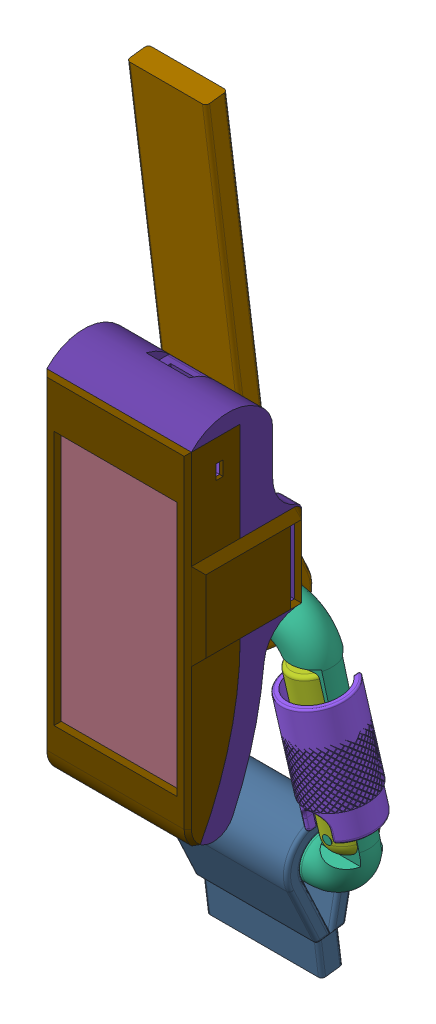
SolidWorks assembly P4_ASSEMBLY, configuration Default. Lengths in mm.
Overall size (66.23 222.78 54.07).
74 component instances, 29 part files, 212 mates.
Components (placement in the parent):
- P4_BTG 3.7V 150mAh LIPO-1: P4_BTG 3.7V 150mAh LIPO [Default] at (27.905 51.2971 -9.81) x (0 -1 0) z (-1 0 0) size (26 7 18.75)
- P4_CAPC-0805-T1.35-BN-1: P4_CAPC-0805-T1.35-BN [Default] at (18.3512 20.3637 -0.675) x (0 1 0) z (-1 0 0) size (2.1 1.35 1.35)
- P4_RESC-0805-1: P4_RESC-0805 [Default] at (24.182 63.4727 0) x (-1 0 0) z (0 0 -1) size (2.1 1.35 0.6)
- P4_RESC-0805-2: P4_RESC-0805 [Default] at (24.1365 57.0909 0) x (-1 0 0) z (0 0 -1) size (2.1 1.35 0.6)
- P4_RESC-0805-4: P4_RESC-0805 [Default] at (24.0502 60.9416 0) x (1 0 0) z (0 0 -1) size (2.1 1.35 0.6)
- P4_soic-14-1: P4_soic-14 [Default] at (16.3896 59.7284 -0.9779) x (0 -1 0) z (1 0 0) size (8.65 1.6 6.05)
- P4_MICRO_SD_WITH_SLOT-1: P4_MICRO_SD_WITH_SLOT [Default] at (56.0581 -187.6439 -121.4036) x (0 0 -1) z (0 1 0) size (2.44 17.9 16)
- P4_MS5611NOBREAKOUT-1: P4_MS5611NOBREAKOUT [Default] at (31.3803 12.3031 -1.5) x (0 1 0) z (-1 0 0) size (5.08 1.5 3.07)
- P4_TACTILE_SWITCH_SIDE-2: P4_TACTILE_SWITCH_SIDE [Default] at (3.8 59.5977 -4.2856) x (0 1 0) z (0 0 1) size (6.8 8.34 8.73)
- P4_BOT-03D PASSIVE BUZZER-1: P4_BOT-03D PASSIVE BUZZER [Default] at (31.8 58.2086 -0.3) x (0 1 0) z (-1 0 0) size (12.6 3.6 11)
- P4_AB2_USB_MICRO_SMD-2: P4_AB2_USB_MICRO_SMD [Default] at (19.0065 148.0155 -12.6975) x (-1 0 0) z (0 1 0) size (7.99 3.56 5.59)
- P4_JST 2pin rightangle-2: P4_JST 2pin rightangle [Default] at (30.445 58.185 -12.31) x (0 1 0) z (1 0 0) size (8 6.3 7.62)
- P4_BLUEFRUIT FEATHER-2: P4_BLUEFRUIT FEATHER [Default] at (30.445 66 -13.81) x (0 -1 0) z (-1 0 0) size (50.98 4.5 22.86)
- P4_1PIN_8.25_SHORT_SOCKET-44: P4_1PIN_8.25_SHORT_SOCKET [Default] at (8.855 24 -12.31) x (0 1 0) z (0 0 1) size (2.54 2.54 11.81)
- P4_1PIN_8.25_SHORT_SOCKET-45: P4_1PIN_8.25_SHORT_SOCKET [Default] at (8.855 26.54 -12.31) x (0 1 0) z (0 0 1) size (2.54 2.54 11.81)
- P4_1PIN_8.25_SHORT_SOCKET-46: P4_1PIN_8.25_SHORT_SOCKET [Default] at (8.855 29.08 -12.31) x (0 1 0) z (0 0 1) size (2.54 2.54 11.81)
- P4_1PIN_8.25_SHORT_SOCKET-47: P4_1PIN_8.25_SHORT_SOCKET [Default] at (8.855 31.62 -12.31) x (0 1 0) z (0 0 1) size (2.54 2.54 11.81)
- P4_1PIN_8.25_SHORT_SOCKET-48: P4_1PIN_8.25_SHORT_SOCKET [Default] at (8.855 34.16 -12.31) x (0 1 0) z (0 0 1) size (2.54 2.54 11.81)
- P4_1PIN_8.25_SHORT_SOCKET-49: P4_1PIN_8.25_SHORT_SOCKET [Default] at (8.855 36.7 -12.31) x (0 1 0) z (0 0 1) size (2.54 2.54 11.81)
- P4_1PIN_8.25_SHORT_SOCKET-50: P4_1PIN_8.25_SHORT_SOCKET [Default] at (8.855 39.24 -12.31) x (0 1 0) z (0 0 1) size (2.54 2.54 11.81)
- P4_1PIN_8.25_SHORT_SOCKET-51: P4_1PIN_8.25_SHORT_SOCKET [Default] at (8.855 41.78 -12.31) x (0 1 0) z (0 0 1) size (2.54 2.54 11.81)
- P4_1PIN_8.25_SHORT_SOCKET-52: P4_1PIN_8.25_SHORT_SOCKET [Default] at (8.855 44.32 -12.31) x (0 1 0) z (0 0 1) size (2.54 2.54 11.81)
- P4_1PIN_8.25_SHORT_SOCKET-53: P4_1PIN_8.25_SHORT_SOCKET [Default] at (8.855 46.86 -12.31) x (0 1 0) z (0 0 1) size (2.54 2.54 11.81)
- P4_1PIN_8.25_SHORT_SOCKET-54: P4_1PIN_8.25_SHORT_SOCKET [Default] at (8.855 49.4 -12.31) x (0 1 0) z (0 0 1) size (2.54 2.54 11.81)
- P4_1PIN_8.25_SHORT_SOCKET-55: P4_1PIN_8.25_SHORT_SOCKET [Default] at (8.855 51.94 -12.31) x (0 1 0) z (0 0 1) size (2.54 2.54 11.81)
- P4_1PIN_8.25_SHORT_SOCKET-56: P4_1PIN_8.25_SHORT_SOCKET [Default] at (8.855 54.48 -12.31) x (0 1 0) z (0 0 1) size (2.54 2.54 11.81)
- P4_1PIN_8.25_SHORT_SOCKET-57: P4_1PIN_8.25_SHORT_SOCKET [Default] at (8.855 57.02 -12.31) x (0 1 0) z (0 0 1) size (2.54 2.54 11.81)
- P4_1PIN_8.25_SHORT_SOCKET-58: P4_1PIN_8.25_SHORT_SOCKET [Default] at (8.855 59.56 -12.31) x (0 1 0) z (0 0 1) size (2.54 2.54 11.81)
- P4_1PIN_8.25_SHORT_SOCKET-59: P4_1PIN_8.25_SHORT_SOCKET [Default] at (8.855 21.46 -12.31) x (0 1 0) z (0 0 1) size (2.54 2.54 11.81)
- P4_1PIN_8.25_SHORT_SOCKET-60: P4_1PIN_8.25_SHORT_SOCKET [Default] at (29.175 49.4 -12.31) x (0 1 0) z (0 0 1) size (2.54 2.54 11.81)
- P4_1PIN_8.25_SHORT_SOCKET-61: P4_1PIN_8.25_SHORT_SOCKET [Default] at (29.175 46.86 -12.31) x (0 1 0) z (0 0 1) size (2.54 2.54 11.81)
- P4_1PIN_8.25_SHORT_SOCKET-62: P4_1PIN_8.25_SHORT_SOCKET [Default] at (29.175 44.32 -12.31) x (0 1 0) z (0 0 1) size (2.54 2.54 11.81)
- P4_1PIN_8.25_SHORT_SOCKET-63: P4_1PIN_8.25_SHORT_SOCKET [Default] at (29.175 41.78 -12.31) x (0 1 0) z (0 0 1) size (2.54 2.54 11.81)
- P4_1PIN_8.25_SHORT_SOCKET-64: P4_1PIN_8.25_SHORT_SOCKET [Default] at (29.175 39.24 -12.31) x (0 1 0) z (0 0 1) size (2.54 2.54 11.81)
- P4_1PIN_8.25_SHORT_SOCKET-65: P4_1PIN_8.25_SHORT_SOCKET [Default] at (29.175 36.7 -12.31) x (0 1 0) z (0 0 1) size (2.54 2.54 11.81)
- P4_1PIN_8.25_SHORT_SOCKET-66: P4_1PIN_8.25_SHORT_SOCKET [Default] at (29.175 34.16 -12.31) x (0 1 0) z (0 0 1) size (2.54 2.54 11.81)
- P4_1PIN_8.25_SHORT_SOCKET-67: P4_1PIN_8.25_SHORT_SOCKET [Default] at (29.175 31.62 -12.31) x (0 1 0) z (0 0 1) size (2.54 2.54 11.81)
- P4_1PIN_8.25_SHORT_SOCKET-68: P4_1PIN_8.25_SHORT_SOCKET [Default] at (29.175 29.08 -12.31) x (0 1 0) z (0 0 1) size (2.54 2.54 11.81)
- P4_1PIN_8.25_SHORT_SOCKET-69: P4_1PIN_8.25_SHORT_SOCKET [Default] at (29.175 26.54 -12.31) x (0 1 0) z (0 0 1) size (2.54 2.54 11.81)
- P4_1PIN_8.25_SHORT_SOCKET-70: P4_1PIN_8.25_SHORT_SOCKET [Default] at (29.175 24 -12.31) x (0 1 0) z (0 0 1) size (2.54 2.54 11.81)
- P4_1PIN_8.25_SHORT_SOCKET-71: P4_1PIN_8.25_SHORT_SOCKET [Default] at (29.175 21.46 -12.31) x (0 1 0) z (0 0 1) size (2.54 2.54 11.81)
- Part2^P4_ASSEMBLY-1: Part2^P4_ASSEMBLY [Default] at origin (virtual)
- P4_2.9_EPD-1: P4_2.9_EPD [Default] at (38 66.02 3.13) x (-1 0 0) z (0 1 0) size (38 8.3 89.5)
  - P4_2.9_EPD-1: P4_2.9_EPD [Default] at origin size (38 3.55 89.5)
  - P4_JST XH 8 S8B-XH-A1 shrouded header connector v4-1: P4_JST XH 8 S8B-XH-A1 shrouded header connector v4 [Default] at (19 -2.875 -82.5) x (-1 0 0) z (0 0 -1) size (22.68 5.75 10.45)
  - P4_FPC_24-1: P4_FPC_24 [Valor predeterminado] at (23 -2.13 -7.2471) x (1 0 0) z (0 1 0) size (16.4 6.45 2.13)
- P4_PCB_FOR_2.9_EPD-1: P4_PCB_FOR_2.9_EPD [Default] at (0 66 1) x (1 0 0) z (0 1 0) size (38 1 66)
- P4_2.9_EPD_CASE_BACK-1: P4_2.9_EPD_CASE_BACK [Default] at (38.015 -27.6516 -35.2894) x (0 1 0) z (-1 0 0) size (100.85 30.49 40)
- P4_2.9_EPD_CASE_COVER-1: P4_2.9_EPD_CASE_COVER [Default] at (0 -6.6251 5.68) x (0 1 0) z (0 0 1) size (95.4 44 31.49)
- P4_SO8-1: P4_SO8 [Default] at (15.2666 50.6882 0) x (1 0 0) z (0 1 0) size (5 1.75 6.2)
- P4_SOT23-1: P4_SOT23 [Predeterminado] at (22.8563 53.2581 -0.6726) x (-1 0 0) z (0 0 -1) size (3 2.25 1.22)
- P4_RESC-0805-8: P4_RESC-0805 [Default] at (22.7629 48.0366 0) x (0 1 0) z (0 0 -1) size (2.1 1.35 0.6)
- P4_878980426-1: P4_878980426 [Default] at (8.84 35.43 -2.565) x (0 1 0) z (-1 0 0) size (10.16 9.65 4.8)
- P4_878980426-2: P4_878980426 [Default] at (8.84 25.27 -2.565) x (0 1 0) z (-1 0 0) size (10.16 9.65 4.8)
- P4_878980426-3: P4_878980426 [Default] at (29.16 35.43 -2.565) x (0 1 0) z (-1 0 0) size (10.16 9.65 4.8)
- P4_878980426-4: P4_878980426 [Default] at (8.84 55.75 -2.565) x (0 1 0) z (-1 0 0) size (10.16 9.65 4.8)
- P4_878980426-5: P4_878980426 [Default] at (29.16 45.59 -2.565) x (0 1 0) z (-1 0 0) size (10.16 9.65 4.8)
- P4_878980426-6: P4_878980426 [Default] at (29.16 25.27 -2.565) x (0 1 0) z (-1 0 0) size (10.16 9.65 4.8)
- P4_878980426-7: P4_878980426 [Default] at (8.84 45.59 -2.565) x (0 1 0) z (-1 0 0) size (10.16 9.65 4.8)
- P4_SPACER-1: P4_SPACER [Default] at (38 -23.48 3.13) x (-1 0 0) z (0 -1 0) size (38 3.13 70.25)
- P4_SMT_RA_PIN-1: P4_SMT_RA_PIN [Default] at (24.03 10.67 0) x (0 -1 0) z (1 0 0) size (12.95 3.56 2.54)
- P4_SMT_RA_PIN-2: P4_SMT_RA_PIN [Default] at (26.57 10.67 0) x (0 -1 0) z (1 0 0) size (12.95 3.56 2.54)
- P4_SMT_RA_PIN-3: P4_SMT_RA_PIN [Default] at (18.95 10.67 0) x (0 -1 0) z (1 0 0) size (12.95 3.56 2.54)
- P4_SMT_RA_PIN-4: P4_SMT_RA_PIN [Default] at (21.49 10.67 0) x (0 -1 0) z (1 0 0) size (12.95 3.56 2.54)
- P4_SMT_RA_PIN-5: P4_SMT_RA_PIN [Default] at (31.65 10.67 0) x (0 -1 0) z (1 0 0) size (12.95 3.56 2.54)
- P4_SMT_RA_PIN-6: P4_SMT_RA_PIN [Default] at (29.11 10.67 0) x (0 -1 0) z (1 0 0) size (12.95 3.56 2.54)
- P4_SMT_RA_PIN-7: P4_SMT_RA_PIN [Default] at (36.73 10.67 0) x (0 -1 0) z (1 0 0) size (12.95 3.56 2.54)
- P4_SMT_RA_PIN-8: P4_SMT_RA_PIN [Default] at (34.19 10.67 0) x (0 -1 0) z (1 0 0) size (12.95 3.56 2.54)
- CARABINER SUP AIR Ø12-1: CARABINER SUP AIR Ø12 [Default] at (19.0561 -21.0823 -30.0124) x (1 0 0) z (0 -0.122208 0.992504) size (66.23 74 18.01)
  - ALÇA-1: ALÇA [Default] at origin size (63.85 74 12.79)
  - GATILHO-1: GATILHO [Default] at (26.2233 -22.952 0) x (0.990404 0.138202 0) z (0 0 1) size (12 45.37 12.12)
  - FECHO-1: FECHO [Default] at (25.3718 -16.8504 0) x (0.990404 0.138202 0) z (0 0 1) size (18.01 33.07 18.01)
- RISER-1: RISER [Default] at (7.015 9.6853 -26.2239) x (1 0 0) z (0 -0.122208 0.992504) size (24 140 20)
- HARNESS-1: HARNESS [Default] at (1.9827 -51.85 -33.8009) x (1 0 0) z (0 0.122208 -0.992504) size (34 40 20)
Mates (geometry in assembly coordinates):
- Coincident628: coincident anti-aligned: plane of P4_BTG 3.7V 150mAh LIPO-1 through (27.905 51.2971 -9.81) normal (0 0 -1); plane of P4_BLUEFRUIT FEATHER-2 through (30.445 66 -9.81) normal (0 0 1)
- Coincident376: coincident aligned: plane of P4_PCB_FOR_2.9_EPD-1 through (0 66 0) normal (-1 0 0); plane of P4_TACTILE_SWITCH_SIDE-2 through (0 59.5977 -4.2856) normal (-1 0 0)
- Coincident433: coincident anti-aligned: plane of P4_AB2_USB_MICRO_SMD-2 through (19.0065 66 -12.31) normal (0 0 -1); plane of P4_BLUEFRUIT FEATHER-2 through (27.815 17.65 -12.31) normal (0 0 1)
- Parallel22: parallel aligned: line of P4_AB2_USB_MICRO_SMD-2 through (21.4522 66 -12.3752) axis (-1 0 0); line of P4_BLUEFRUIT FEATHER-2 through (27.815 66 -12.31) axis (-1 0 0)
- Coincident434: coincident aligned: plane of P4_JST 2pin rightangle-2 through (30.445 52.4192 -12.31) normal (1 0 0); plane of P4_BLUEFRUIT FEATHER-2 through (30.445 63.37 -12.31) normal (1 0 0)
- Coincident435: coincident: line of P4_AB2_USB_MICRO_SMD-2 through (21.9513 66 -9.7692) axis (-1 0 0); plane of P4_BLUEFRUIT FEATHER-2 through (27.815 66 -12.31) normal (0 1 0)
- Coincident436: coincident anti-aligned: plane of P4_JST 2pin rightangle-2 through (26.635 55.3021 -12.31) normal (0 0 -1); plane of P4_BLUEFRUIT FEATHER-2 through (27.815 17.65 -12.31) normal (0 0 1)
- Distance27: distance = 6.7 mm aligned: plane of P4_JST 2pin rightangle-2 through (30.445 59.3 -12.31) normal (0 1 0); plane of P4_BLUEFRUIT FEATHER-2 through (27.815 66 -12.31) normal (0 1 0)
- Parallel23: parallel aligned: plane of P4_BOT-03D PASSIVE BUZZER-1 through (38 55.7086 -3.6) normal (1 0 0); plane of P4_BLUEFRUIT FEATHER-2 through (30.445 63.37 -12.31) normal (1 0 0)
- LimitDistance11: limit distance = 0.0071 mm anti-aligned: plane of P4_BTG 3.7V 150mAh LIPO-1 through (27.905 51.2971 -2.81) normal (0 1 0); plane of P4_JST 2pin rightangle-2 through (30.445 51.3042 -12.31) normal (0 -1 0)
- Coincident458: coincident aligned: plane of P4_1PIN_8.25_SHORT_SOCKET-57 through (7.585 57.02 -3.81) normal (-1 0 0); plane of P4_1PIN_8.25_SHORT_SOCKET-58 through (7.585 59.56 -3.81) normal (-1 0 0)
- Coincident459: coincident aligned: plane of P4_1PIN_8.25_SHORT_SOCKET-56 through (7.585 54.48 -3.81) normal (-1 0 0); plane of P4_1PIN_8.25_SHORT_SOCKET-57 through (7.585 57.02 -3.81) normal (-1 0 0)
- Coincident460: coincident aligned: plane of P4_1PIN_8.25_SHORT_SOCKET-55 through (7.585 51.94 -3.81) normal (-1 0 0); plane of P4_1PIN_8.25_SHORT_SOCKET-56 through (7.585 54.48 -3.81) normal (-1 0 0)
- Coincident461: coincident aligned: plane of P4_1PIN_8.25_SHORT_SOCKET-54 through (7.585 49.4 -3.81) normal (-1 0 0); plane of P4_1PIN_8.25_SHORT_SOCKET-55 through (7.585 51.94 -3.81) normal (-1 0 0)
- Coincident462: coincident aligned: plane of P4_1PIN_8.25_SHORT_SOCKET-53 through (7.585 46.86 -3.81) normal (-1 0 0); plane of P4_1PIN_8.25_SHORT_SOCKET-54 through (7.585 49.4 -3.81) normal (-1 0 0)
- Coincident463: coincident aligned: plane of P4_1PIN_8.25_SHORT_SOCKET-52 through (7.585 44.32 -3.81) normal (-1 0 0); plane of P4_1PIN_8.25_SHORT_SOCKET-53 through (7.585 46.86 -3.81) normal (-1 0 0)
- Coincident464: coincident aligned: plane of P4_1PIN_8.25_SHORT_SOCKET-51 through (7.585 41.78 -3.81) normal (-1 0 0); plane of P4_1PIN_8.25_SHORT_SOCKET-52 through (7.585 44.32 -3.81) normal (-1 0 0)
- Coincident465: coincident aligned: plane of P4_1PIN_8.25_SHORT_SOCKET-50 through (7.585 39.24 -3.81) normal (-1 0 0); plane of P4_1PIN_8.25_SHORT_SOCKET-51 through (7.585 41.78 -3.81) normal (-1 0 0)
- Coincident466: coincident aligned: plane of P4_1PIN_8.25_SHORT_SOCKET-49 through (7.585 36.7 -3.81) normal (-1 0 0); plane of P4_1PIN_8.25_SHORT_SOCKET-50 through (7.585 39.24 -3.81) normal (-1 0 0)
- Coincident467: coincident aligned: plane of P4_1PIN_8.25_SHORT_SOCKET-48 through (7.585 34.16 -3.81) normal (-1 0 0); plane of P4_1PIN_8.25_SHORT_SOCKET-49 through (7.585 36.7 -3.81) normal (-1 0 0)
- Coincident468: coincident aligned: plane of P4_1PIN_8.25_SHORT_SOCKET-47 through (7.585 31.62 -3.81) normal (-1 0 0); plane of P4_1PIN_8.25_SHORT_SOCKET-48 through (7.585 34.16 -3.81) normal (-1 0 0)
- Coincident469: coincident aligned: plane of P4_1PIN_8.25_SHORT_SOCKET-46 through (7.585 29.08 -3.81) normal (-1 0 0); plane of P4_1PIN_8.25_SHORT_SOCKET-47 through (7.585 31.62 -3.81) normal (-1 0 0)
- Coincident470: coincident aligned: plane of P4_1PIN_8.25_SHORT_SOCKET-45 through (7.585 26.54 -3.81) normal (-1 0 0); plane of P4_1PIN_8.25_SHORT_SOCKET-46 through (7.585 29.08 -3.81) normal (-1 0 0)
- Coincident471: coincident aligned: plane of P4_1PIN_8.25_SHORT_SOCKET-44 through (7.585 24 -3.81) normal (-1 0 0); plane of P4_1PIN_8.25_SHORT_SOCKET-45 through (7.585 26.54 -3.81) normal (-1 0 0)
- Coincident472: coincident anti-aligned: plane of P4_1PIN_8.25_SHORT_SOCKET-57 through (8.855 58.29 -3.81) normal (0 1 0); plane of P4_1PIN_8.25_SHORT_SOCKET-58 through (8.855 58.29 -3.81) normal (0 -1 0)
- Coincident473: coincident anti-aligned: plane of P4_1PIN_8.25_SHORT_SOCKET-56 through (8.855 55.75 -3.81) normal (0 1 0); plane of P4_1PIN_8.25_SHORT_SOCKET-57 through (8.855 55.75 -3.81) normal (0 -1 0)
- Coincident474: coincident anti-aligned: plane of P4_1PIN_8.25_SHORT_SOCKET-55 through (8.855 53.21 -3.81) normal (0 1 0); plane of P4_1PIN_8.25_SHORT_SOCKET-56 through (8.855 53.21 -3.81) normal (0 -1 0)
- Coincident475: coincident anti-aligned: plane of P4_1PIN_8.25_SHORT_SOCKET-54 through (8.855 50.67 -3.81) normal (0 1 0); plane of P4_1PIN_8.25_SHORT_SOCKET-55 through (8.855 50.67 -3.81) normal (0 -1 0)
- Coincident476: coincident anti-aligned: plane of P4_1PIN_8.25_SHORT_SOCKET-53 through (8.855 48.13 -3.81) normal (0 1 0); plane of P4_1PIN_8.25_SHORT_SOCKET-54 through (8.855 48.13 -3.81) normal (0 -1 0)
- Coincident477: coincident anti-aligned: plane of P4_1PIN_8.25_SHORT_SOCKET-52 through (8.855 45.59 -3.81) normal (0 1 0); plane of P4_1PIN_8.25_SHORT_SOCKET-53 through (8.855 45.59 -3.81) normal (0 -1 0)
- Coincident478: coincident anti-aligned: plane of P4_1PIN_8.25_SHORT_SOCKET-51 through (8.855 43.05 -3.81) normal (0 1 0); plane of P4_1PIN_8.25_SHORT_SOCKET-52 through (8.855 43.05 -3.81) normal (0 -1 0)
- Coincident479: coincident anti-aligned: plane of P4_1PIN_8.25_SHORT_SOCKET-50 through (8.855 40.51 -3.81) normal (0 1 0); plane of P4_1PIN_8.25_SHORT_SOCKET-51 through (8.855 40.51 -3.81) normal (0 -1 0)
- Coincident480: coincident anti-aligned: plane of P4_1PIN_8.25_SHORT_SOCKET-49 through (8.855 37.97 -3.81) normal (0 1 0); plane of P4_1PIN_8.25_SHORT_SOCKET-50 through (8.855 37.97 -3.81) normal (0 -1 0)
- Coincident481: coincident anti-aligned: plane of P4_1PIN_8.25_SHORT_SOCKET-48 through (8.855 35.43 -3.81) normal (0 1 0); plane of P4_1PIN_8.25_SHORT_SOCKET-49 through (8.855 35.43 -3.81) normal (0 -1 0)
- Coincident482: coincident anti-aligned: plane of P4_1PIN_8.25_SHORT_SOCKET-47 through (8.855 32.89 -3.81) normal (0 1 0); plane of P4_1PIN_8.25_SHORT_SOCKET-48 through (8.855 32.89 -3.81) normal (0 -1 0)
- Coincident483: coincident anti-aligned: plane of P4_1PIN_8.25_SHORT_SOCKET-46 through (8.855 30.35 -3.81) normal (0 1 0); plane of P4_1PIN_8.25_SHORT_SOCKET-47 through (8.855 30.35 -3.81) normal (0 -1 0)
- Coincident484: coincident anti-aligned: plane of P4_1PIN_8.25_SHORT_SOCKET-45 through (8.855 27.81 -3.81) normal (0 1 0); plane of P4_1PIN_8.25_SHORT_SOCKET-46 through (8.855 27.81 -3.81) normal (0 -1 0)
- Coincident485: coincident anti-aligned: plane of P4_1PIN_8.25_SHORT_SOCKET-44 through (8.855 25.27 -3.81) normal (0 1 0); plane of P4_1PIN_8.25_SHORT_SOCKET-45 through (8.855 25.27 -3.81) normal (0 -1 0)
- Coincident486: coincident aligned: plane of P4_1PIN_8.25_SHORT_SOCKET-57 through (8.855 57.02 -3.81) normal (0 0 1); plane of P4_1PIN_8.25_SHORT_SOCKET-58 through (8.855 59.56 -3.81) normal (0 0 1)
- Coincident487: coincident aligned: plane of P4_1PIN_8.25_SHORT_SOCKET-56 through (8.855 54.48 -3.81) normal (0 0 1); plane of P4_1PIN_8.25_SHORT_SOCKET-57 through (8.855 57.02 -3.81) normal (0 0 1)
- Coincident488: coincident aligned: plane of P4_1PIN_8.25_SHORT_SOCKET-55 through (8.855 51.94 -3.81) normal (0 0 1); plane of P4_1PIN_8.25_SHORT_SOCKET-56 through (8.855 54.48 -3.81) normal (0 0 1)
- Coincident489: coincident aligned: plane of P4_1PIN_8.25_SHORT_SOCKET-54 through (8.855 49.4 -3.81) normal (0 0 1); plane of P4_1PIN_8.25_SHORT_SOCKET-55 through (8.855 51.94 -3.81) normal (0 0 1)
- Coincident490: coincident aligned: plane of P4_1PIN_8.25_SHORT_SOCKET-53 through (8.855 46.86 -3.81) normal (0 0 1); plane of P4_1PIN_8.25_SHORT_SOCKET-54 through (8.855 49.4 -3.81) normal (0 0 1)
- Coincident491: coincident aligned: plane of P4_1PIN_8.25_SHORT_SOCKET-52 through (8.855 44.32 -3.81) normal (0 0 1); plane of P4_1PIN_8.25_SHORT_SOCKET-53 through (8.855 46.86 -3.81) normal (0 0 1)
- Coincident492: coincident aligned: plane of P4_1PIN_8.25_SHORT_SOCKET-51 through (8.855 41.78 -3.81) normal (0 0 1); plane of P4_1PIN_8.25_SHORT_SOCKET-52 through (8.855 44.32 -3.81) normal (0 0 1)
- Coincident493: coincident aligned: plane of P4_1PIN_8.25_SHORT_SOCKET-50 through (8.855 39.24 -3.81) normal (0 0 1); plane of P4_1PIN_8.25_SHORT_SOCKET-51 through (8.855 41.78 -3.81) normal (0 0 1)
- Coincident494: coincident aligned: plane of P4_1PIN_8.25_SHORT_SOCKET-49 through (8.855 36.7 -3.81) normal (0 0 1); plane of P4_1PIN_8.25_SHORT_SOCKET-50 through (8.855 39.24 -3.81) normal (0 0 1)
- Coincident495: coincident aligned: plane of P4_1PIN_8.25_SHORT_SOCKET-48 through (8.855 34.16 -3.81) normal (0 0 1); plane of P4_1PIN_8.25_SHORT_SOCKET-49 through (8.855 36.7 -3.81) normal (0 0 1)
- Coincident496: coincident aligned: plane of P4_1PIN_8.25_SHORT_SOCKET-47 through (8.855 31.62 -3.81) normal (0 0 1); plane of P4_1PIN_8.25_SHORT_SOCKET-48 through (8.855 34.16 -3.81) normal (0 0 1)
- Coincident497: coincident aligned: plane of P4_1PIN_8.25_SHORT_SOCKET-46 through (8.855 29.08 -3.81) normal (0 0 1); plane of P4_1PIN_8.25_SHORT_SOCKET-47 through (8.855 31.62 -3.81) normal (0 0 1)
- Coincident498: coincident aligned: plane of P4_1PIN_8.25_SHORT_SOCKET-45 through (8.855 26.54 -3.81) normal (0 0 1); plane of P4_1PIN_8.25_SHORT_SOCKET-46 through (8.855 29.08 -3.81) normal (0 0 1)
- Coincident499: coincident aligned: plane of P4_1PIN_8.25_SHORT_SOCKET-44 through (8.855 24 -3.81) normal (0 0 1); plane of P4_1PIN_8.25_SHORT_SOCKET-45 through (8.855 26.54 -3.81) normal (0 0 1)
- Coincident500: coincident anti-aligned: plane of P4_BLUEFRUIT FEATHER-2 through (27.815 17.65 -12.31) normal (0 0 1); plane of P4_1PIN_8.25_SHORT_SOCKET-44 through (8.855 24 -12.31) normal (0 0 -1)
- Coincident501: coincident aligned: plane of P4_1PIN_8.25_SHORT_SOCKET-58 through (7.585 59.56 -3.81) normal (-1 0 0); plane of P4_BLUEFRUIT FEATHER-2 through (7.585 63.37 -12.31) normal (-1 0 0)
- Coincident502: coincident aligned: plane of P4_1PIN_8.25_SHORT_SOCKET-44 through (7.585 24 -3.81) normal (-1 0 0); plane of P4_1PIN_8.25_SHORT_SOCKET-59 through (7.585 21.46 -3.81) normal (-1 0 0)
- Coincident503: coincident anti-aligned: plane of P4_1PIN_8.25_SHORT_SOCKET-44 through (8.855 22.73 -3.81) normal (0 -1 0); plane of P4_1PIN_8.25_SHORT_SOCKET-59 through (8.855 22.73 -3.81) normal (0 1 0)
- Coincident504: coincident aligned: plane of P4_1PIN_8.25_SHORT_SOCKET-44 through (8.855 24 -3.81) normal (0 0 1); plane of P4_1PIN_8.25_SHORT_SOCKET-59 through (8.855 21.46 -3.81) normal (0 0 1)
- Width9: width anti-aligned: plane of P4_1PIN_8.25_SHORT_SOCKET-58 through (8.855 60.83 -3.81) normal (0 1 0); plane of P4_1PIN_8.25_SHORT_SOCKET-59 through (8.855 20.19 -3.81) normal (0 -1 0); plane of P4_BLUEFRUIT FEATHER-2 through (27.815 15.02 -12.31) normal (0 -1 0); plane of P4_BLUEFRUIT FEATHER-2 through (27.815 66 -12.31) normal (0 1 0)
- Coincident505: coincident anti-aligned: plane of P4_1PIN_8.25_SHORT_SOCKET-60 through (29.175 48.13 -3.81) normal (0 -1 0); plane of P4_1PIN_8.25_SHORT_SOCKET-61 through (29.175 48.13 -3.81) normal (0 1 0)
- Coincident506: coincident anti-aligned: plane of P4_1PIN_8.25_SHORT_SOCKET-70 through (29.175 22.73 -3.81) normal (0 -1 0); plane of P4_1PIN_8.25_SHORT_SOCKET-71 through (29.175 22.73 -3.81) normal (0 1 0)
- Coincident507: coincident aligned: plane of P4_1PIN_8.25_SHORT_SOCKET-63 through (27.905 41.78 -3.81) normal (-1 0 0); plane of P4_1PIN_8.25_SHORT_SOCKET-64 through (27.905 39.24 -3.81) normal (-1 0 0)
- Coincident508: coincident aligned: plane of P4_1PIN_8.25_SHORT_SOCKET-61 through (27.905 46.86 -3.81) normal (-1 0 0); plane of P4_1PIN_8.25_SHORT_SOCKET-62 through (27.905 44.32 -3.81) normal (-1 0 0)
- Coincident509: coincident aligned: plane of P4_1PIN_8.25_SHORT_SOCKET-62 through (27.905 44.32 -3.81) normal (-1 0 0); plane of P4_1PIN_8.25_SHORT_SOCKET-63 through (27.905 41.78 -3.81) normal (-1 0 0)
- Coincident510: coincident aligned: plane of P4_1PIN_8.25_SHORT_SOCKET-66 through (27.905 34.16 -3.81) normal (-1 0 0); plane of P4_1PIN_8.25_SHORT_SOCKET-67 through (27.905 31.62 -3.81) normal (-1 0 0)
- Coincident511: coincident aligned: plane of P4_1PIN_8.25_SHORT_SOCKET-65 through (27.905 36.7 -3.81) normal (-1 0 0); plane of P4_1PIN_8.25_SHORT_SOCKET-66 through (27.905 34.16 -3.81) normal (-1 0 0)
- Coincident512: coincident aligned: plane of P4_1PIN_8.25_SHORT_SOCKET-68 through (27.905 29.08 -3.81) normal (-1 0 0); plane of P4_1PIN_8.25_SHORT_SOCKET-69 through (27.905 26.54 -3.81) normal (-1 0 0)
- Coincident513: coincident aligned: plane of P4_1PIN_8.25_SHORT_SOCKET-67 through (27.905 31.62 -3.81) normal (-1 0 0); plane of P4_1PIN_8.25_SHORT_SOCKET-68 through (27.905 29.08 -3.81) normal (-1 0 0)
- Coincident514: coincident aligned: plane of P4_1PIN_8.25_SHORT_SOCKET-69 through (27.905 26.54 -3.81) normal (-1 0 0); plane of P4_1PIN_8.25_SHORT_SOCKET-70 through (27.905 24 -3.81) normal (-1 0 0)
- Coincident515: coincident aligned: plane of P4_1PIN_8.25_SHORT_SOCKET-70 through (27.905 24 -3.81) normal (-1 0 0); plane of P4_1PIN_8.25_SHORT_SOCKET-71 through (27.905 21.46 -3.81) normal (-1 0 0)
- Coincident516: coincident aligned: plane of P4_1PIN_8.25_SHORT_SOCKET-60 through (27.905 49.4 -3.81) normal (-1 0 0); plane of P4_1PIN_8.25_SHORT_SOCKET-61 through (27.905 46.86 -3.81) normal (-1 0 0)
- Coincident517: coincident aligned: plane of P4_1PIN_8.25_SHORT_SOCKET-64 through (27.905 39.24 -3.81) normal (-1 0 0); plane of P4_1PIN_8.25_SHORT_SOCKET-65 through (27.905 36.7 -3.81) normal (-1 0 0)
- Coincident518: coincident anti-aligned: plane of P4_1PIN_8.25_SHORT_SOCKET-62 through (29.175 43.05 -3.81) normal (0 -1 0); plane of P4_1PIN_8.25_SHORT_SOCKET-63 through (29.175 43.05 -3.81) normal (0 1 0)
- Coincident519: coincident anti-aligned: plane of P4_1PIN_8.25_SHORT_SOCKET-63 through (29.175 40.51 -3.81) normal (0 -1 0); plane of P4_1PIN_8.25_SHORT_SOCKET-64 through (29.175 40.51 -3.81) normal (0 1 0)
- Coincident520: coincident anti-aligned: plane of P4_1PIN_8.25_SHORT_SOCKET-65 through (29.175 35.43 -3.81) normal (0 -1 0); plane of P4_1PIN_8.25_SHORT_SOCKET-66 through (29.175 35.43 -3.81) normal (0 1 0)
- Coincident521: coincident anti-aligned: plane of P4_1PIN_8.25_SHORT_SOCKET-66 through (29.175 32.89 -3.81) normal (0 -1 0); plane of P4_1PIN_8.25_SHORT_SOCKET-67 through (29.175 32.89 -3.81) normal (0 1 0)
- Coincident522: coincident anti-aligned: plane of P4_1PIN_8.25_SHORT_SOCKET-61 through (29.175 45.59 -3.81) normal (0 -1 0); plane of P4_1PIN_8.25_SHORT_SOCKET-62 through (29.175 45.59 -3.81) normal (0 1 0)
- Coincident523: coincident anti-aligned: plane of P4_1PIN_8.25_SHORT_SOCKET-67 through (29.175 30.35 -3.81) normal (0 -1 0); plane of P4_1PIN_8.25_SHORT_SOCKET-68 through (29.175 30.35 -3.81) normal (0 1 0)
- Coincident524: coincident anti-aligned: plane of P4_1PIN_8.25_SHORT_SOCKET-69 through (29.175 25.27 -3.81) normal (0 -1 0); plane of P4_1PIN_8.25_SHORT_SOCKET-70 through (29.175 25.27 -3.81) normal (0 1 0)
- Coincident525: coincident anti-aligned: plane of P4_1PIN_8.25_SHORT_SOCKET-64 through (29.175 37.97 -3.81) normal (0 -1 0); plane of P4_1PIN_8.25_SHORT_SOCKET-65 through (29.175 37.97 -3.81) normal (0 1 0)
- Coincident526: coincident anti-aligned: plane of P4_1PIN_8.25_SHORT_SOCKET-68 through (29.175 27.81 -3.81) normal (0 -1 0); plane of P4_1PIN_8.25_SHORT_SOCKET-69 through (29.175 27.81 -3.81) normal (0 1 0)
- Coincident527: coincident aligned: plane of P4_1PIN_8.25_SHORT_SOCKET-65 through (29.175 36.7 -3.81) normal (0 0 1); plane of P4_1PIN_8.25_SHORT_SOCKET-66 through (29.175 34.16 -3.81) normal (0 0 1)
- Coincident528: coincident aligned: plane of P4_1PIN_8.25_SHORT_SOCKET-68 through (29.175 29.08 -3.81) normal (0 0 1); plane of P4_1PIN_8.25_SHORT_SOCKET-69 through (29.175 26.54 -3.81) normal (0 0 1)
- Coincident529: coincident aligned: plane of P4_1PIN_8.25_SHORT_SOCKET-62 through (29.175 44.32 -3.81) normal (0 0 1); plane of P4_1PIN_8.25_SHORT_SOCKET-63 through (29.175 41.78 -3.81) normal (0 0 1)
- Coincident530: coincident aligned: plane of P4_1PIN_8.25_SHORT_SOCKET-64 through (29.175 39.24 -3.81) normal (0 0 1); plane of P4_1PIN_8.25_SHORT_SOCKET-65 through (29.175 36.7 -3.81) normal (0 0 1)
- Coincident531: coincident aligned: plane of P4_1PIN_8.25_SHORT_SOCKET-70 through (29.175 24 -3.81) normal (0 0 1); plane of P4_1PIN_8.25_SHORT_SOCKET-71 through (29.175 21.46 -3.81) normal (0 0 1)
- Coincident532: coincident aligned: plane of P4_1PIN_8.25_SHORT_SOCKET-63 through (29.175 41.78 -3.81) normal (0 0 1); plane of P4_1PIN_8.25_SHORT_SOCKET-64 through (29.175 39.24 -3.81) normal (0 0 1)
- Coincident533: coincident aligned: plane of P4_1PIN_8.25_SHORT_SOCKET-60 through (29.175 49.4 -3.81) normal (0 0 1); plane of P4_1PIN_8.25_SHORT_SOCKET-61 through (29.175 46.86 -3.81) normal (0 0 1)
- Coincident534: coincident aligned: plane of P4_1PIN_8.25_SHORT_SOCKET-61 through (29.175 46.86 -3.81) normal (0 0 1); plane of P4_1PIN_8.25_SHORT_SOCKET-62 through (29.175 44.32 -3.81) normal (0 0 1)
- Coincident535: coincident aligned: plane of P4_1PIN_8.25_SHORT_SOCKET-67 through (29.175 31.62 -3.81) normal (0 0 1); plane of P4_1PIN_8.25_SHORT_SOCKET-68 through (29.175 29.08 -3.81) normal (0 0 1)
- Coincident536: coincident aligned: plane of P4_1PIN_8.25_SHORT_SOCKET-66 through (29.175 34.16 -3.81) normal (0 0 1); plane of P4_1PIN_8.25_SHORT_SOCKET-67 through (29.175 31.62 -3.81) normal (0 0 1)
- Coincident537: coincident aligned: plane of P4_1PIN_8.25_SHORT_SOCKET-69 through (29.175 26.54 -3.81) normal (0 0 1); plane of P4_1PIN_8.25_SHORT_SOCKET-70 through (29.175 24 -3.81) normal (0 0 1)
- Coincident538: coincident aligned: plane of P4_BLUEFRUIT FEATHER-2 through (30.445 63.37 -12.31) normal (1 0 0); plane of P4_1PIN_8.25_SHORT_SOCKET-71 through (30.445 21.46 -3.81) normal (1 0 0)
- Coincident539: coincident aligned: plane of P4_1PIN_8.25_SHORT_SOCKET-59 through (8.855 20.19 -3.81) normal (0 -1 0); plane of P4_1PIN_8.25_SHORT_SOCKET-71 through (29.175 20.19 -3.81) normal (0 -1 0)
- Coincident540: coincident aligned: plane of P4_1PIN_8.25_SHORT_SOCKET-59 through (8.855 21.46 -3.81) normal (0 0 1); plane of P4_1PIN_8.25_SHORT_SOCKET-71 through (29.175 21.46 -3.81) normal (0 0 1)
- Coincident627: coincident anti-aligned: plane of P4_BTG 3.7V 150mAh LIPO-1 through (27.905 51.2971 -2.81) normal (1 0 0); plane of P4_1PIN_8.25_SHORT_SOCKET-60 through (27.905 49.4 -3.81) normal (-1 0 0)
- Parallel29: parallel aligned: plane of P4_BLUEFRUIT FEATHER-2 through (30.445 63.37 -12.31) normal (1 0 0); plane of P4_2.9_EPD-1/P4_2.9_EPD-1 through (38 64.52 4.63) normal (1 0 0)
- Coincident640: coincident aligned: plane of P4_BLUEFRUIT FEATHER-2 through (27.815 66 -12.31) normal (0 1 0); plane of P4_PCB_FOR_2.9_EPD-1 through (0 66 0) normal (0 1 0)
- Concentric36: concentric aligned: cylinder of P4_BLUEFRUIT FEATHER-2 through (10.125 17.65 -12.31) axis (0 0 -1) radius 1.5; cylinder of P4_2.9_EPD_CASE_BACK-1 through (10.125 17.65 -12.31) axis (0 0 -1) radius 1.5
- Concentric37: concentric aligned: cylinder of P4_BLUEFRUIT FEATHER-2 through (18.17 7.7595 -20.355) axis (0 1 0) radius 1.5; cylinder of P4_2.9_EPD_CASE_BACK-1 through (18.17 7.2595 -20.355) axis (0 1 0) radius 1.5
- Coincident642: coincident anti-aligned: plane of P4_BLUEFRUIT FEATHER-2 through (27.815 17.65 -13.81) normal (0 0 -1); plane of P4_2.9_EPD_CASE_BACK-1 through (0.015 -27.6516 -13.81) normal (0 0 1)
- Concentric38: concentric anti-aligned: cylinder of P4_2.9_EPD-1/P4_2.9_EPD-1 through (2.5 63.52 4.63) axis (0 0 -1) radius 1.25; cylinder of P4_2.9_EPD_CASE_COVER-1 through (2.5 63.52 2.68) axis (0 0 1) radius 1.25
- Concentric39: concentric anti-aligned: cylinder of P4_2.9_EPD-1/P4_2.9_EPD-1 through (35.5 63.52 4.63) axis (0 0 -1) radius 1.25; cylinder of P4_2.9_EPD_CASE_COVER-1 through (35.5 63.52 2.68) axis (0 0 1) radius 1.25
- Coincident645: coincident anti-aligned: plane of P4_2.9_EPD-1/P4_2.9_EPD-1 through (38 66.02 5.68) normal (0 0 1); plane of P4_2.9_EPD_CASE_COVER-1 through (0 -6.6251 5.68) normal (0 0 -1)
- Distance28: distance = 8.2058 mm: line of P4_AB2_USB_MICRO_SMD-2 through (15.7873 63.7041 -12.0707) axis (0 -1 0); line of P4_BLUEFRUIT FEATHER-2 through (7.585 63.37 -12.31) axis (0 -1 0)
- Width11: width anti-aligned: plane of P4_2.9_EPD-1/P4_2.9_EPD-1 through (0 64.52 4.63) normal (-1 0 0); plane of P4_2.9_EPD-1/P4_2.9_EPD-1 through (38 64.52 4.63) normal (1 0 0); plane of P4_PCB_FOR_2.9_EPD-1 through (38 66 0) normal (1 0 0); plane of P4_PCB_FOR_2.9_EPD-1 through (0 66 0) normal (-1 0 0)
- Coincident648: coincident anti-aligned: plane of P4_2.9_EPD-1/P4_2.9_EPD-1 through (10 66.02 4.63) normal (0 1 0); plane of P4_2.9_EPD_CASE_BACK-1 through (0.015 66.02 -35.2894) normal (0 -1 0)
- Coincident650: coincident anti-aligned: plane of P4_CAPC-0805-T1.35-BN-1 through (18.3512 20.3637 0) normal (0 0 1); plane of P4_PCB_FOR_2.9_EPD-1 through (0 66 0) normal (0 0 -1)
- Coincident651: coincident anti-aligned: plane of P4_MS5611NOBREAKOUT-1 through (31.3803 12.3031 0) normal (0 0 1); plane of P4_PCB_FOR_2.9_EPD-1 through (0 66 0) normal (0 0 -1)
- Coincident652: coincident anti-aligned: plane of P4_TACTILE_SWITCH_SIDE-2 through (4.917 56.1977 0) normal (0 0 1); plane of P4_PCB_FOR_2.9_EPD-1 through (0 66 0) normal (0 0 -1)
- Coincident653: coincident anti-aligned: plane of P4_MICRO_SD_WITH_SLOT-1 through (6.0767 17.9614 0) normal (0 0 1); plane of P4_PCB_FOR_2.9_EPD-1 through (0 66 0) normal (0 0 -1)
- Coincident654: coincident: line of P4_soic-14-1 through (13.3812 56.1026 0) axis (0 -1 0); plane of P4_PCB_FOR_2.9_EPD-1 through (0 66 0) normal (0 0 -1)
- Coincident655: coincident: line of P4_soic-14-1 through (19.398 55.7343 0) axis (0 1 0); plane of P4_PCB_FOR_2.9_EPD-1 through (0 66 0) normal (0 0 -1)
- Coincident656: coincident anti-aligned: plane of P4_RESC-0805-2 through (23.1365 56.4159 0) normal (0 0 1); plane of P4_PCB_FOR_2.9_EPD-1 through (0 66 0) normal (0 0 -1)
- Coincident657: coincident anti-aligned: plane of P4_RESC-0805-1 through (23.182 62.7977 0) normal (0 0 1); plane of P4_PCB_FOR_2.9_EPD-1 through (0 66 0) normal (0 0 -1)
- Coincident658: coincident anti-aligned: plane of P4_RESC-0805-4 through (23.4002 61.6166 0) normal (0 0 1); plane of P4_PCB_FOR_2.9_EPD-1 through (0 66 0) normal (0 0 -1)
- Coincident659: coincident anti-aligned: plane of P4_PCB_FOR_2.9_EPD-1 through (0 66 0) normal (0 0 -1); plane of P4_RESC-0805-8 through (22.0879 49.0366 0) normal (0 0 1)
- Coincident660: coincident anti-aligned: plane of P4_PCB_FOR_2.9_EPD-1 through (0 66 0) normal (0 0 -1); plane of P4_SOT23-1 through (21.3443 52.317 0) normal (0 0 1)
- Coincident661: coincident anti-aligned: plane of P4_PCB_FOR_2.9_EPD-1 through (0 66 0) normal (0 0 -1); plane of P4_SO8-1 through (16.9716 53.1882 0) normal (0 0 1)
- Parallel31: parallel aligned: line of P4_PCB_FOR_2.9_EPD-1 through (0 66 0) axis (1 0 0); line of P4_SO8-1 through (15.7016 53.7882 0) axis (1 0 0)
- Coincident663: coincident anti-aligned: plane of P4_878980426-3 through (29.16 40.51 -2.565) normal (0 1 0); plane of P4_878980426-5 through (29.16 40.51 -2.565) normal (0 -1 0)
- Coincident664: coincident aligned: plane of P4_878980426-3 through (30.415 30.35 -1.32) normal (1 0 0); plane of P4_878980426-5 through (30.415 40.51 -1.32) normal (1 0 0)
- Coincident665: coincident aligned: plane of P4_878980426-3 through (30.415 30.35 -3.81) normal (0 0 -1); plane of P4_878980426-5 through (30.415 40.51 -3.81) normal (0 0 -1)
- Coincident666: coincident aligned: plane of P4_878980426-3 through (30.415 30.35 -3.81) normal (0 0 -1); plane of P4_878980426-6 through (30.415 20.19 -3.81) normal (0 0 -1)
- Coincident667: coincident aligned: plane of P4_878980426-3 through (30.415 30.35 -1.32) normal (1 0 0); plane of P4_878980426-6 through (30.415 20.19 -1.32) normal (1 0 0)
- Coincident668: coincident anti-aligned: plane of P4_878980426-3 through (29.16 30.35 -2.565) normal (0 -1 0); plane of P4_878980426-6 through (29.16 30.35 -2.565) normal (0 1 0)
- Coincident669: coincident aligned: plane of P4_878980426-4 through (10.095 50.67 -1.32) normal (1 0 0); plane of P4_878980426-7 through (10.095 40.51 -1.32) normal (1 0 0)
- Coincident670: coincident aligned: plane of P4_878980426-4 through (10.095 50.67 -3.81) normal (0 0 -1); plane of P4_878980426-7 through (10.095 40.51 -3.81) normal (0 0 -1)
- Coincident671: coincident anti-aligned: plane of P4_878980426-4 through (8.84 50.67 -2.565) normal (0 -1 0); plane of P4_878980426-7 through (8.84 50.67 -2.565) normal (0 1 0)
- Coincident672: coincident anti-aligned: plane of P4_878980426-1 through (8.84 40.51 -2.565) normal (0 1 0); plane of P4_878980426-7 through (8.84 40.51 -2.565) normal (0 -1 0)
- Coincident673: coincident aligned: plane of P4_878980426-1 through (10.095 30.35 -3.81) normal (0 0 -1); plane of P4_878980426-7 through (10.095 40.51 -3.81) normal (0 0 -1)
- Coincident674: coincident aligned: plane of P4_878980426-1 through (10.095 30.35 -1.32) normal (1 0 0); plane of P4_878980426-7 through (10.095 40.51 -1.32) normal (1 0 0)
- Coincident675: coincident anti-aligned: plane of P4_878980426-1 through (8.84 30.35 -2.565) normal (0 -1 0); plane of P4_878980426-2 through (8.84 30.35 -2.565) normal (0 1 0)
- Coincident676: coincident aligned: plane of P4_878980426-1 through (10.095 30.35 -1.32) normal (1 0 0); plane of P4_878980426-2 through (10.095 20.19 -1.32) normal (1 0 0)
- Coincident677: coincident aligned: plane of P4_878980426-1 through (10.095 30.35 -3.81) normal (0 0 -1); plane of P4_878980426-2 through (10.095 20.19 -3.81) normal (0 0 -1)
- Coincident678: coincident anti-aligned: plane of P4_PCB_FOR_2.9_EPD-1 through (0 66 0) normal (0 0 -1); plane of P4_878980426-4 through (6.44 59.24 0) normal (0 0 1)
- Coincident679: coincident aligned: plane of P4_878980426-4 through (10.095 50.67 -3.81) normal (0 0 -1); plane of P4_878980426-5 through (30.415 40.51 -3.81) normal (0 0 -1)
- Coincident680: coincident aligned: plane of P4_878980426-2 through (8.84 20.19 -2.565) normal (0 -1 0); plane of P4_878980426-6 through (29.16 20.19 -2.565) normal (0 -1 0)
- Coincident681: coincident anti-aligned: plane of P4_BOT-03D PASSIVE BUZZER-1 through (31.8 58.2086 0) normal (0 0 1); plane of P4_PCB_FOR_2.9_EPD-1 through (0 66 0) normal (0 0 -1)
- Coincident682: coincident aligned: plane of P4_1PIN_8.25_SHORT_SOCKET-59 through (7.585 21.46 -3.81) normal (-1 0 0); plane of P4_878980426-2 through (7.585 20.19 -3.81) normal (-1 0 0)
- Coincident683: coincident aligned: plane of P4_1PIN_8.25_SHORT_SOCKET-59 through (8.855 20.19 -3.81) normal (0 -1 0); plane of P4_878980426-2 through (8.84 20.19 -2.565) normal (0 -1 0)
- Coincident684: coincident aligned: plane of P4_1PIN_8.25_SHORT_SOCKET-71 through (27.905 21.46 -3.81) normal (-1 0 0); plane of P4_878980426-6 through (27.905 20.19 -3.81) normal (-1 0 0)
- LimitDistance19: limit distance = 0 mm anti-aligned: plane of P4_878980426-2 through (10.095 20.19 -3.81) normal (0 0 -1); plane of P4_1PIN_8.25_SHORT_SOCKET-59 through (8.855 21.46 -3.81) normal (0 0 1)
- Width12: width anti-aligned: plane of P4_PCB_FOR_2.9_EPD-1 through (0 66 0) normal (-1 0 0); plane of P4_PCB_FOR_2.9_EPD-1 through (38 66 0) normal (1 0 0); plane of P4_878980426-6 through (30.415 20.19 -1.32) normal (1 0 0); plane of P4_878980426-2 through (7.585 20.19 -3.81) normal (-1 0 0)
- Coincident690: coincident anti-aligned: plane of P4_2.9_EPD-1/P4_2.9_EPD-1 through (1.5 64.52 3.13) normal (0 0 -1); plane of P4_SPACER-1 through (1.5 64.52 3.13) normal (0 0 1)
- Concentric40: concentric aligned: cylinder of P4_2.9_EPD_CASE_COVER-1 through (35.5 63.52 2.68) axis (0 0 1) radius 1.25; cylinder of P4_SPACER-1 through (35.5 63.52 1) axis (0 0 1) radius 1.25
- Coincident691: coincident anti-aligned: plane of P4_2.9_EPD_CASE_COVER-1 through (38 -23.98 -0.32) normal (-1 0 0); plane of P4_SPACER-1 through (38 -4.23 1) normal (1 0 0)
- LimitDistance21: limit distance = 2.5527 mm anti-aligned: plane of P4_SPACER-1; plane of P4_PCB_FOR_2.9_EPD-1
- Coincident692: coincident anti-aligned: plane of P4_SMT_RA_PIN-1 through (21.49 10.67 -3.56) normal (-1 0 0); plane of P4_SMT_RA_PIN-4 through (21.49 10.67 -3.56) normal (1 0 0)
- Coincident693: coincident aligned: plane of P4_SMT_RA_PIN-1 through (24.03 10.67 -3.56) normal (0 0 -1); plane of P4_SMT_RA_PIN-4 through (21.49 10.67 -3.56) normal (0 0 -1)
- Coincident694: coincident aligned: plane of P4_SMT_RA_PIN-1 through (24.03 10.67 -3.56) normal (0 1 0); plane of P4_SMT_RA_PIN-4 through (21.49 10.67 -3.56) normal (0 1 0)
- Coincident695: coincident aligned: plane of P4_SMT_RA_PIN-3 through (18.95 10.67 -3.56) normal (0 1 0); plane of P4_SMT_RA_PIN-4 through (21.49 10.67 -3.56) normal (0 1 0)
- Coincident696: coincident aligned: plane of P4_SMT_RA_PIN-3 through (18.95 10.67 -3.56) normal (0 0 -1); plane of P4_SMT_RA_PIN-4 through (21.49 10.67 -3.56) normal (0 0 -1)
- Coincident697: coincident anti-aligned: plane of P4_SMT_RA_PIN-3 through (18.95 10.67 -3.56) normal (1 0 0); plane of P4_SMT_RA_PIN-4 through (18.95 10.67 -3.56) normal (-1 0 0)
- Coincident698: coincident anti-aligned: plane of P4_SMT_RA_PIN-1 through (24.03 10.67 -3.56) normal (1 0 0); plane of P4_SMT_RA_PIN-2 through (24.03 10.67 -3.56) normal (-1 0 0)
- Coincident699: coincident aligned: plane of P4_SMT_RA_PIN-1 through (24.03 10.67 -3.56) normal (0 1 0); plane of P4_SMT_RA_PIN-2 through (26.57 10.67 -3.56) normal (0 1 0)
- Coincident700: coincident aligned: plane of P4_SMT_RA_PIN-1 through (24.03 10.67 -3.56) normal (0 0 -1); plane of P4_SMT_RA_PIN-2 through (26.57 10.67 -3.56) normal (0 0 -1)
- Coincident701: coincident aligned: plane of P4_SMT_RA_PIN-5 through (31.65 10.67 -3.56) normal (0 0 -1); plane of P4_SMT_RA_PIN-6 through (29.11 10.67 -3.56) normal (0 0 -1)
- Coincident702: coincident aligned: plane of P4_SMT_RA_PIN-5 through (31.65 10.67 -3.56) normal (0 1 0); plane of P4_SMT_RA_PIN-8 through (34.19 10.67 -3.56) normal (0 1 0)
- Coincident703: coincident aligned: plane of P4_SMT_RA_PIN-5 through (31.65 10.67 -3.56) normal (0 0 -1); plane of P4_SMT_RA_PIN-8 through (34.19 10.67 -3.56) normal (0 0 -1)
- Coincident704: coincident anti-aligned: plane of P4_SMT_RA_PIN-7 through (34.19 10.67 -3.56) normal (-1 0 0); plane of P4_SMT_RA_PIN-8 through (34.19 10.67 -3.56) normal (1 0 0)
- Coincident705: coincident aligned: plane of P4_SMT_RA_PIN-5 through (31.65 10.67 -3.56) normal (0 1 0); plane of P4_SMT_RA_PIN-6 through (29.11 10.67 -3.56) normal (0 1 0)
- Coincident706: coincident aligned: plane of P4_SMT_RA_PIN-7 through (36.73 10.67 -3.56) normal (0 1 0); plane of P4_SMT_RA_PIN-8 through (34.19 10.67 -3.56) normal (0 1 0)
- Coincident707: coincident anti-aligned: plane of P4_SMT_RA_PIN-5 through (29.11 10.67 -3.56) normal (-1 0 0); plane of P4_SMT_RA_PIN-6 through (29.11 10.67 -3.56) normal (1 0 0)
- Coincident708: coincident aligned: plane of P4_SMT_RA_PIN-7 through (36.73 10.67 -3.56) normal (0 0 -1); plane of P4_SMT_RA_PIN-8 through (34.19 10.67 -3.56) normal (0 0 -1)
- Coincident709: coincident anti-aligned: plane of P4_SMT_RA_PIN-5 through (31.65 10.67 -3.56) normal (1 0 0); plane of P4_SMT_RA_PIN-8 through (31.65 10.67 -3.56) normal (-1 0 0)
- Coincident710: coincident anti-aligned: plane of P4_SMT_RA_PIN-2 through (26.57 10.67 -3.56) normal (1 0 0); plane of P4_SMT_RA_PIN-6 through (26.57 10.67 -3.56) normal (-1 0 0)
- Coincident711: coincident aligned: plane of P4_SMT_RA_PIN-2 through (26.57 10.67 0) normal (0 0 1); plane of P4_SMT_RA_PIN-6 through (29.11 10.67 0) normal (0 0 1)
- Coincident712: coincident aligned: plane of P4_SMT_RA_PIN-2 through (26.57 10.67 -3.56) normal (0 1 0); plane of P4_SMT_RA_PIN-6 through (29.11 10.67 -3.56) normal (0 1 0)
- Coincident713: coincident anti-aligned: plane of P4_PCB_FOR_2.9_EPD-1 through (0 66 0) normal (0 0 -1); plane of P4_SMT_RA_PIN-7 through (35.78 15.24 0) normal (0 0 1)
- Distance32: distance = 15.24 mm anti-aligned: plane of P4_PCB_FOR_2.9_EPD-1 through (0 0 0) normal (0 -1 0); plane of P4_SMT_RA_PIN-7 through (36.73 15.24 0) normal (0 1 0)
- Distance33: distance = 1.27 mm anti-aligned: plane of P4_2.9_EPD_CASE_COVER-1 through (38 -23.98 -0.32) normal (-1 0 0); plane of P4_SMT_RA_PIN-7 through (36.73 10.67 -3.56) normal (1 0 0)
- Coincident718: coincident anti-aligned: plane of P4_PCB_FOR_2.9_EPD-1 through (0 0 0) normal (0 -1 0); plane of assembly through (0 0 0) normal (0 1 0)
- Coincident719: coincident anti-aligned: plane of P4_PCB_FOR_2.9_EPD-1 through (0 66 0) normal (0 0 -1); plane of assembly through (0 0 0) normal (0 0 1)
- Coincident720: coincident anti-aligned: plane of P4_PCB_FOR_2.9_EPD-1 through (0 66 0) normal (-1 0 0); plane of assembly through (0 0 0) normal (1 0 0)
- Coincident722: coincident aligned: plane of P4_BOT-03D PASSIVE BUZZER-1 through (38 55.7086 -3.6) normal (1 0 0); plane of P4_PCB_FOR_2.9_EPD-1 through (38 66 0) normal (1 0 0)
- Parallel32: parallel anti-aligned: line of P4_PCB_FOR_2.9_EPD-1 through (38 66 0) axis (0 -1 0); line of P4_SOT23-1 through (21.3563 52.5581 -0.6726) axis (0 1 0)
- Parallel36: parallel anti-aligned: plane of P4_soic-14-1 through (18.763 55.7343 -0.3556) normal (0 -1 0); plane of P4_PCB_FOR_2.9_EPD-1 through (0 66 0) normal (0 1 0)
- Parallel37: parallel anti-aligned: plane of P4_PCB_FOR_2.9_EPD-1 through (0 66 0) normal (0 1 0); plane of P4_RESC-0805-8 through (22.0879 46.9866 -0.05) normal (0 -1 0)
- Concentric41: concentric anti-aligned: cylinder of CARABINER SUP AIR Ø12-1/ALÇA-1 through (7.0971 9.6853 -26.2239) axis (1 0 0) radius 6; cylinder of RISER-1 through (31.015 9.6853 -26.2239) axis (-1 0 0) radius 6
- Coincident723: coincident anti-aligned: circle of CARABINER SUP AIR Ø12-1/ALÇA-1; plane of RISER-1 through (31.015 9.6853 -26.2239) normal (1 0 0)
- Parallel38: parallel: plane of CARABINER SUP AIR Ø12-1/ALÇA-1 through (50.9827 2.3834 -24.2011) normal (0 -0.122208 0.992504); line of RISER-1 through (30.015 138.4665 -8.3518) axis (0 -0.992504 -0.122208)
- Width13: width anti-aligned: plane of RISER-1 through (31.015 9.6853 -26.2239) normal (1 0 0); plane of RISER-1 through (7.015 9.6853 -26.2239) normal (-1 0 0); plane of P4_2.9_EPD_CASE_BACK-1 through (-0.985 15.02 85.011) normal (-1 0 0); plane of P4_2.9_EPD_CASE_BACK-1 through (39.015 15.02 85.011) normal (1 0 0)
- Concentric42: concentric aligned: cylinder of CARABINER SUP AIR Ø12-1/ALÇA-1 through (35.9827 -51.85 -33.8009) axis (-1 0 0) radius 6; cylinder of HARNESS-1 through (35.9827 -51.85 -33.8009) axis (-1 0 0) radius 6
- Coincident726: coincident aligned: circle of CARABINER SUP AIR Ø12-1/ALÇA-1; plane of HARNESS-1 through (35.9827 -51.85 -33.8009) normal (1 0 0)
- Parallel40: parallel aligned: plane of RISER-1 through (30.015 29.902 -26.7573) normal (0 0.122208 -0.992504); plane of HARNESS-1 through (2.9827 -71.3334 -39.2226) normal (0 0.122208 -0.992504)
- Width17: width anti-aligned: plane of P4_2.9_EPD_CASE_BACK-1 through (-0.985 15.02 85.011) normal (-1 0 0); plane of P4_2.9_EPD_CASE_BACK-1 through (39.015 15.02 85.011) normal (1 0 0); plane of RISER-1 through (30.015 29.1688 -20.8023) normal (1 0 0); plane of RISER-1 through (8.015 29.902 -26.7573) normal (-1 0 0)
- Tangent14: tangent anti-aligned: cylinder of P4_2.9_EPD_CASE_BACK-1 through (0.015 61.1009 -8.81) axis (1 0 0) radius 8; plane of RISER-1 through (8.015 29.1688 -20.8023) normal (0 -0.122208 0.992504)
- Tangent12: tangent anti-aligned: cylinder of P4_2.9_EPD_CASE_BACK-1 through (0.015 14.6229 -6.81) axis (1 0 0) radius 10; plane of RISER-1 through (31.015 11.5986 -16.4087) normal (0 0.191326 0.981527)
- Tangent13: tangent anti-aligned: cylinder of P4_2.9_EPD_CASE_BACK-1 through (0.015 16.9203 -22.81) axis (1 0 0) radius 2; cylinder of CARABINER SUP AIR Ø12-1/ALÇA-1 through (7.0971 9.6853 -26.2239) axis (1 0 0) radius 6
- Distance36: distance = 2.2774 mm aligned: plane of P4_soic-14-1 through (18.763 63.7226 -0.3556) normal (0 1 0); plane of P4_PCB_FOR_2.9_EPD-1 through (0 66 0) normal (0 1 0)
- Distance37: distance = 19.6546 mm aligned: plane of P4_soic-14-1 through (18.3454 64.0464 -0.9779) normal (1 0 0); plane of P4_PCB_FOR_2.9_EPD-1 through (38 66 0) normal (1 0 0)
- Distance38: distance = 1.8523 mm aligned: plane of P4_RESC-0805-1 through (24.182 64.1477 0) normal (0 1 0); plane of P4_PCB_FOR_2.9_EPD-1 through (0 66 0) normal (0 1 0)
- Distance39: distance = 12.768 mm aligned: plane of P4_RESC-0805-1 through (25.232 62.7977 -0.05) normal (1 0 0); plane of P4_PCB_FOR_2.9_EPD-1 through (38 66 0) normal (1 0 0)
- Distance40: distance = 4.3834 mm aligned: plane of P4_RESC-0805-4 through (24.0502 61.6166 0) normal (0 1 0); plane of P4_PCB_FOR_2.9_EPD-1 through (0 66 0) normal (0 1 0)
- Distance41: distance = 12.8998 mm aligned: plane of P4_RESC-0805-4 through (25.1002 61.6166 -0.53) normal (1 0 0); plane of P4_PCB_FOR_2.9_EPD-1 through (38 66 0) normal (1 0 0)
- Distance42: distance = 8.2341 mm aligned: plane of P4_RESC-0805-2 through (24.1365 57.7659 0) normal (0 1 0); plane of P4_PCB_FOR_2.9_EPD-1 through (0 66 0) normal (0 1 0)
- Distance43: distance = 12.8135 mm aligned: plane of P4_RESC-0805-2 through (25.1865 56.4159 -0.05) normal (1 0 0); plane of P4_PCB_FOR_2.9_EPD-1 through (38 66 0) normal (1 0 0)
- Distance44: distance = 1.4914 mm aligned: plane of P4_BOT-03D PASSIVE BUZZER-1 through (31 64.5086 0) normal (0 1 0); plane of P4_PCB_FOR_2.9_EPD-1 through (0 66 0) normal (0 1 0)
- Distance45: distance = 14.5621 mm aligned: plane of P4_RESC-0805-8 through (23.4379 48.0366 0) normal (1 0 0); plane of P4_PCB_FOR_2.9_EPD-1 through (38 66 0) normal (1 0 0)
- Distance46: distance = 16.9134 mm aligned: plane of P4_RESC-0805-8 through (22.0879 49.0866 -0.53) normal (0 1 0); plane of P4_PCB_FOR_2.9_EPD-1 through (0 66 0) normal (0 1 0)
- Distance47: distance = 11.6162 mm aligned: plane of P4_SOT23-1 through (22.6145 54.3838 0.0174) normal (0 1 0); plane of P4_PCB_FOR_2.9_EPD-1 through (0 66 0) normal (0 1 0)
- Distance48: distance = 14.902 mm aligned: plane of P4_SOT23-1 through (23.098 54.3838 0.0174) normal (1 0 0); plane of P4_PCB_FOR_2.9_EPD-1 through (38 66 0) normal (1 0 0)
- Distance49: distance = 12.2118 mm aligned: plane of P4_SO8-1 through (16.9716 53.7882 0) normal (0 1 0); plane of P4_PCB_FOR_2.9_EPD-1 through (0 66 0) normal (0 1 0)
- Distance50: distance = 20.6284 mm aligned: plane of P4_SO8-1 through (17.3716 48.6882 -1) normal (1 0 0); plane of P4_PCB_FOR_2.9_EPD-1 through (38 66 0) normal (1 0 0)
- Distance51: distance = 3.0023 mm aligned: plane of P4_TACTILE_SWITCH_SIDE-2 through (5.4229 62.9977 3.1769) normal (0 1 0); plane of P4_PCB_FOR_2.9_EPD-1 through (0 66 0) normal (0 1 0)
- Distance52: distance = 15.1191 mm aligned: plane of P4_MS5611NOBREAKOUT-1 through (22.8809 19.1344 0) normal (1 0 0); plane of P4_PCB_FOR_2.9_EPD-1 through (38 66 0) normal (1 0 0)
- Distance53: distance = 41.7884 mm aligned: plane of P4_MS5611NOBREAKOUT-1 through (22.8809 24.2116 0) normal (0 1 0); plane of P4_PCB_FOR_2.9_EPD-1 through (0 66 0) normal (0 1 0)
- Distance54: distance = 19.6488 mm aligned: plane of P4_CAPC-0805-T1.35-BN-1 through (18.3512 21.4137 0) normal (1 0 0); plane of P4_PCB_FOR_2.9_EPD-1 through (38 66 0) normal (1 0 0)
- Distance55: distance = 44.5863 mm aligned: plane of P4_CAPC-0805-T1.35-BN-1 through (17.0012 21.4137 0) normal (0 1 0); plane of P4_PCB_FOR_2.9_EPD-1 through (0 66 0) normal (0 1 0)
- Distance56: distance = 0.8733 mm aligned: plane of P4_MICRO_SD_WITH_SLOT-1 through (-0.8733 13.4164 -1.82) normal (-1 0 0); plane of P4_PCB_FOR_2.9_EPD-1 through (0 66 0) normal (-1 0 0)
- Distance57: distance = 3.2164 mm aligned: plane of P4_MICRO_SD_WITH_SLOT-1 through (-0.0733 3.2164 -1.82) normal (0 -1 0); plane of P4_PCB_FOR_2.9_EPD-1 through (0 0 0) normal (0 -1 0)
- Coincident761: coincident anti-aligned: plane of P4_PCB_FOR_2.9_EPD-1 through (0 66 1) normal (0 0 1); plane of P4_SPACER-1 through (1.5 64.52 1) normal (0 0 -1)
